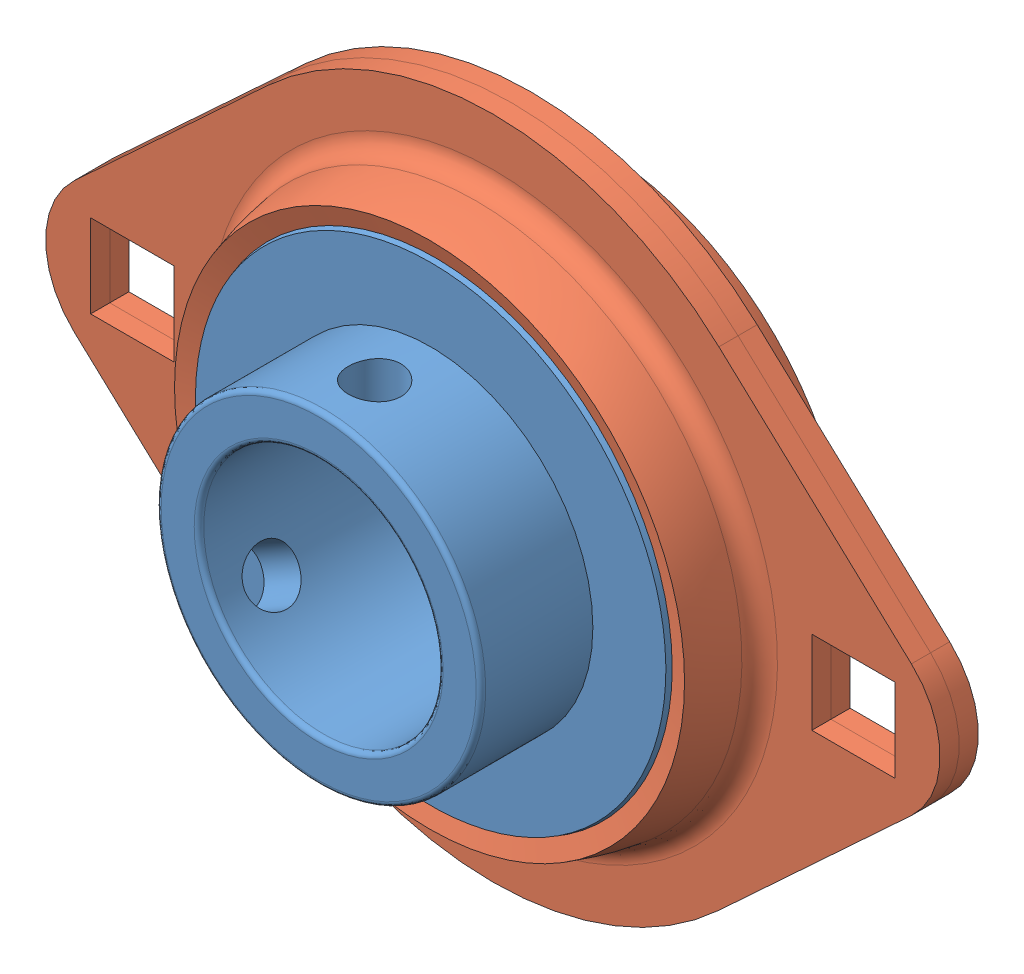
SolidWorks assembly Подшипник 205 самоуст-в-сборе, configuration 00. Lengths in mm.
Overall size (93.45 69.5 34.2).
3 component instances, 2 part files, 6 mates.
Components (placement in the parent):
- Подшипник 205 самоуст-1: Подшипник 205 самоуст [--] at origin size (52 52 34.2)
- Обойма подшипника 205 самоуст-1: Обойма подшипника 205 самоуст [--] at (0 0 -17) x (1 0 0) z (0 -1 0) size (93.45 8.62 69.5)
- Обойма подшипника 205 самоуст-2: Обойма подшипника 205 самоуст [--] x (-1 0 0) z (0 -1 0) size (93.45 8.62 69.5)
Mates (geometry in assembly coordinates):
- Концентричный1: concentric: sphere of Подшипник 205 самоуст-1; sphere of Обойма подшипника 205 самоуст-1
- Параллельность1: parallel: plane of Подшипник 205 самоуст-1 through (0 16.95 11.7) normal (0 0 1); plane of Обойма подшипника 205 самоуст-1 through (34.75 0 -6.5) normal (0 0 1)
- Совпадение2: coincident: plane of Подшипник 205 самоуст-1 through (0 0 0) normal (0 1 0); plane of Обойма подшипника 205 самоуст-1 through (0 0 -17) normal (0 -1 0)
- Совпадение3: coincident: plane of Обойма подшипника 205 самоуст-1 through (34.75 0 -8.5) normal (0 0 -1); plane of Обойма подшипника 205 самоуст-2 through (-34.75 0 -8.5) normal (0 0 1)
- Совпадение4: coincident: plane of Обойма подшипника 205 самоуст-1 through (-42.025 -4.35 0.1154) normal (1 0 0); plane of Обойма подшипника 205 самоуст-2 through (-42.025 -4.35 -17.1154) normal (1 0 0)
- Совпадение5: coincident: plane of Обойма подшипника 205 самоуст-1 through (42.025 -4.35 0.1154) normal (0 1 0); plane of Обойма подшипника 205 самоуст-2 through (42.025 -4.35 -17.1154) normal (0 1 0)
